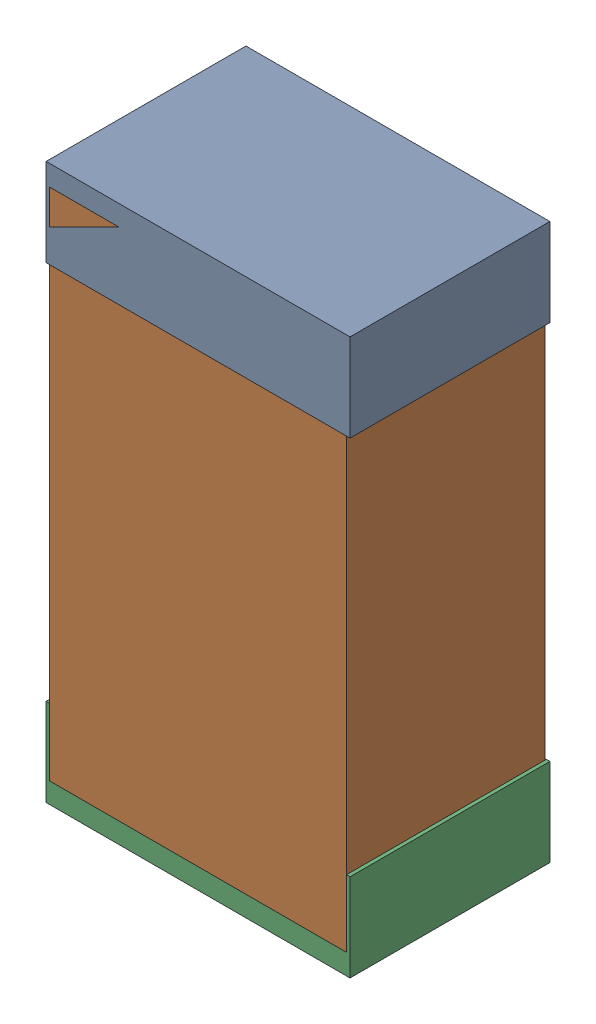
SolidWorks assembly R21Kanaloa_v2.0.0_Motor, configuration Default. Lengths in mm.
Overall size (1.3 2.38 0.85).
6 component instances, 2 part files, 0 mates.
Components (placement in the parent):
- 330415056-1: 330415056 [Default] at (123.952 66.024 -1.9574) size (1.3 0.38 0.85)
  - Extruded_2-1: Extruded_2 [Default] at origin size (1.3 0.38 0.85)
- 334787376-1: 334787376 [Default] at (123.952 65.024 -1.9524) size (1.27 2.2 0.85)
  - Extruded_16-1: Extruded_16 [Default] at origin size (1.27 2.2 0.85)
- 330415056-2: 330415056 [Default] at (123.952 64.024 -1.9574) size (1.3 0.38 0.85)
  - Extruded_2-1: Extruded_2 [Default] at origin size (1.3 0.38 0.85)
